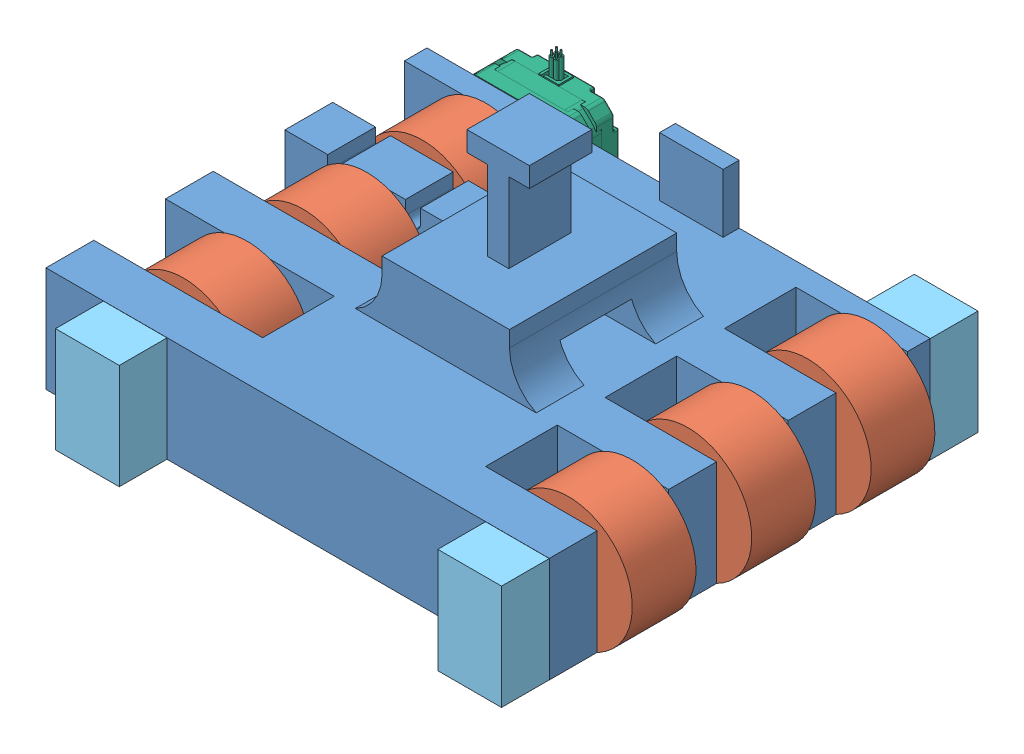
SolidWorks assembly Assembly1, configuration Default. Lengths in mm.
Overall size (224.34 121.01 190.92).
13 component instances, 6 part files, 36 mates.
Components (placement in the parent):
- Baseplate-1: Baseplate [Default] at origin size (200.66 105.14 151.88)
- Spool-1: Spool [Default] at (75.9415 19.1844 -1.5875) x (-0.044193 0.999023 0) z (-0.999023 -0.044193 0) size (50.8 25.4 50.8)
- Spool-2: Spool [Default] at (75.9415 19.1844 -49.2125) x (-0.843083 -0.537783 0) z (0.537783 -0.843083 0) size (50.8 25.4 50.8)
- Spool-4: Spool [Default] at (-77.5755 17.9234 -96.8375) x (0.161917 -0.986804 0) z (0.986804 0.161917 0) size (50.8 25.4 50.8)
- Spool-5: Spool [Default] at (-77.5755 17.9234 -49.2125) x (-0.773639 -0.633626 0) z (0.633626 -0.773639 0) size (50.8 25.4 50.8)
- Driven Axle-1: Driven Axle [Default] at (-77.5755 17.9234 -123.825) x (-0.773639 -0.633626 0) z (-0.633626 0.773639 0) size (10.56 151.89 12.19)
- Short Axle-1: Short Axle [Default] at (75.9415 19.1844 -142.35) x (-0.887276 0.46124 0) z (0.46124 0.887276 0) size (10.56 170.92 12.19)
- Axle Cap-1: Axle Cap [Default] at (76.2 19.05 -132.825) x (0 1 0) z (-1 0 0) size (41.91 28.58 25.4)
- Axle Cap-2: Axle Cap [Default] at (76.2 19.05 19.05) x (0 -1 0) z (-1 0 0) size (41.91 28.58 25.4)
- Axle Cap-3: Axle Cap [Default] at (-76.2 19.05 19.05) x (0 1 0) z (1 0 0) size (41.91 28.58 25.4)
- Spool-6: Spool [Default] at (-77.5755 17.9234 -26.9875) x (-0.773639 -0.633626 0) z (-0.633626 0.773639 0) size (50.8 25.4 50.8)
- 17HS08-1004S-1: 17HS08-1004S [По умолчанию] at (-76.2 19.05 -152.825) x (-1 0 0) z (0 1 0) size (42 40 51.2)
- Spool-7: Spool [Default] at (75.9415 19.1844 -96.8375) x (0.843083 0.537783 0) z (-0.537783 0.843083 0) size (50.8 25.4 50.8)
Mates (geometry in assembly coordinates):
- Coincident1: coincident: cylinder of Baseplate-1 through (-76.2 19.05 19.05) axis (0 0 -1) radius 6.35; line of Driven Axle-1 through (-73.7129 13.2073 28.067) axis (0 0 -1)
- Coincident2: coincident: cylinder of Baseplate-1 through (-76.2 19.05 19.05) axis (0 0 -1) radius 6.35; line of Driven Axle-1 through (-81.4381 22.6395 28.067) axis (0 0 -1)
- Coincident4: coincident: cylinder of Baseplate-1 through (76.2 19.05 19.05) axis (0 0 -1) radius 6.35; line of Short Axle-1 through (72.6632 24.3238 28.5742) axis (0 0 -1)
- Coincident5: coincident: cylinder of Baseplate-1 through (76.2 19.05 19.05) axis (0 0 -1) radius 6.35; line of Short Axle-1 through (69.8514 18.915 28.5742) axis (0 0 -1)
- Concentric1: concentric aligned: cylinder of Baseplate-1 through (76.2 34.925 9.525) axis (0 0 1) radius 3.175; cylinder of Axle Cap-2 through (76.2 34.925 9.525) axis (0 0 1) radius 3.175
- Concentric6: concentric aligned: cylinder of Baseplate-1 through (76.2 3.175 9.525) axis (0 0 1) radius 3.175; cylinder of Axle Cap-2 through (76.2 3.175 9.525) axis (0 0 1) radius 3.175
- Coincident10: coincident anti-aligned: plane of Baseplate-1 through (0 0 19.05) normal (0 0 1); plane of Axle Cap-2 through (76.2 19.05 19.05) normal (0 0 -1)
- Distance1: distance = 1.5875 mm anti-aligned: plane of Spool-1 through (75.9415 19.1844 -26.9875) normal (0 0 -1); plane of Baseplate-1 through (25.4 38.1 -28.575) normal (0 0 1)
- Distance2: distance = 1.5875 mm anti-aligned: plane of Spool-2 through (75.9415 19.1844 -49.2125) normal (0 0 1); plane of Baseplate-1 through (25.4 50.8 -47.625) normal (0 0 -1)
- Concentric7: concentric aligned: cylinder of Baseplate-1 through (76.2 34.925 -123.3) axis (0 0 -1) radius 3.175; cylinder of Axle Cap-1 through (76.2 34.925 -123.3) axis (0 0 -1) radius 3.175
- Concentric8: concentric aligned: cylinder of Baseplate-1 through (76.2 3.175 -123.3) axis (0 0 -1) radius 3.175; cylinder of Axle Cap-1 through (76.2 3.175 -123.3) axis (0 0 -1) radius 3.175
- Concentric9: concentric aligned: cylinder of Baseplate-1 through (-76.2 3.175 9.525) axis (0 0 1) radius 3.175; cylinder of Axle Cap-3 through (-76.2 3.175 9.525) axis (0 0 1) radius 3.175
- Concentric10: concentric aligned: cylinder of Baseplate-1 through (-76.2 34.925 9.525) axis (0 0 1) radius 3.175; cylinder of Axle Cap-3 through (-76.2 34.925 9.525) axis (0 0 1) radius 3.175
- Coincident27: coincident anti-aligned: plane of Baseplate-1 through (0 0 -123.825) normal (0 0 1); plane of Driven Axle-1 through (-77.5755 17.9234 -123.825) normal (0 0 -1)
- Distance3: distance = 1.5875 mm anti-aligned: plane of Spool-4 through (-77.5755 17.9234 -122.2375) normal (0 0 -1); plane of Baseplate-1 through (0 0 -123.825) normal (0 0 1)
- Distance4: distance = 1.5875 mm anti-aligned: plane of Spool-5 through (-77.5755 17.9234 -74.6125) normal (0 0 -1); plane of Baseplate-1 through (25.4 50.8 -76.2) normal (0 0 1)
- Distance5: distance = 1.5875 mm anti-aligned: plane of Spool-6 through (-77.5755 17.9234 -1.5875) normal (0 0 1); plane of Baseplate-1 through (0 0 0) normal (0 0 -1)
- Concentric11: concentric anti-aligned: cylinder of Baseplate-1 through (-91.7 34.55 -132.825) axis (0 0 1) radius 2; cylinder of 17HS08-1004S-1 through (-91.7 34.55 -132.825) axis (0 0 -1) radius 1.5
- Concentric12: concentric anti-aligned: cylinder of Baseplate-1 through (-60.7 34.55 -132.825) axis (0 0 1) radius 2; cylinder of 17HS08-1004S-1 through (-60.7 34.55 -132.825) axis (0 0 -1) radius 1.5
- Coincident35: coincident anti-aligned: plane of Baseplate-1 through (0 0 -132.825) normal (0 0 -1); plane of 17HS08-1004S-1 through (-76.2 19.05 -132.825) normal (0 0 1)
- Coincident37: coincident anti-aligned: plane of Short Axle-1 through (75.9415 19.1844 -142.35) normal (0 0 -1); plane of Axle Cap-1 through (76.2 19.05 -142.35) normal (0 0 1)
- Distance6: distance = 1.5875 mm anti-aligned: plane of Spool-7 through (75.9415 19.1844 -96.8375) normal (0 0 1); plane of Baseplate-1 through (127 38.1 -95.25) normal (0 0 -1)
- Coincident44: coincident anti-aligned: plane of Baseplate-1 through (0 0 -132.825) normal (0 0 -1); plane of Axle Cap-1 through (76.2 19.05 -132.825) normal (0 0 1)
- Coincident45: coincident anti-aligned: plane of Baseplate-1 through (0 0 19.05) normal (0 0 1); plane of Axle Cap-3 through (-76.2 19.05 19.05) normal (0 0 -1)
- Width1: width anti-aligned: plane of Spool-1 through (82.2853 19.465 -26.9875) normal (-0.887276 0.46124 0); plane of Spool-1 through (69.5977 18.9038 -26.9875) normal (0.887276 -0.46124 0); plane of Short Axle-1 through (80.6257 16.7494 28.5742) normal (0.887276 -0.46124 0); plane of Short Axle-1 through (71.2573 21.6194 28.5742) normal (-0.887276 0.46124 0)
- Width2: width anti-aligned: plane of Spool-1 through (79.3564 13.8308 -26.9875) normal (-0.044193 0.999023 0); plane of Spool-1 through (72.5266 24.538 -26.9875) normal (0.044193 -0.999023 0); plane of Short Axle-1 through (76.1748 13.9103 28.5742) normal (0.044193 -0.999023 0); plane of Short Axle-1 through (75.7082 24.4585 28.5742) normal (-0.044193 0.999023 0)
- Width3: width anti-aligned: plane of Spool-2 through (82.2853 19.465 -74.6125) normal (-0.887276 0.46124 0); plane of Spool-2 through (69.5977 18.9038 -74.6125) normal (0.887276 -0.46124 0); plane of Short Axle-1 through (80.6257 16.7494 28.5742) normal (0.887276 -0.46124 0); plane of Short Axle-1 through (71.2573 21.6194 28.5742) normal (-0.887276 0.46124 0)
- Width4: width anti-aligned: plane of Spool-2 through (79.3564 13.8308 -74.6125) normal (-0.044193 0.999023 0); plane of Spool-2 through (72.5266 24.538 -74.6125) normal (0.044193 -0.999023 0); plane of Short Axle-1 through (76.1748 13.9103 28.5742) normal (0.044193 -0.999023 0); plane of Short Axle-1 through (75.7082 24.4585 28.5742) normal (-0.044193 0.999023 0)
- Width5: width anti-aligned: plane of Spool-7 through (82.2853 19.465 -122.2375) normal (-0.887276 0.46124 0); plane of Spool-7 through (69.5977 18.9038 -122.2375) normal (0.887276 -0.46124 0); plane of Short Axle-1 through (80.6257 16.7494 28.5742) normal (0.887276 -0.46124 0); plane of Short Axle-1 through (71.2573 21.6194 28.5742) normal (-0.887276 0.46124 0)
- Width6: width anti-aligned: plane of Spool-7 through (79.3564 13.8308 -122.2375) normal (-0.044193 0.999023 0); plane of Spool-7 through (72.5266 24.538 -122.2375) normal (0.044193 -0.999023 0); plane of Short Axle-1 through (76.1748 13.9103 28.5742) normal (0.044193 -0.999023 0); plane of Short Axle-1 through (75.7082 24.4585 28.5742) normal (-0.044193 0.999023 0)
- Width7: width aligned: plane of Spool-4 through (-79.8182 11.9826 -122.2375) normal (0.773639 0.633626 0); plane of Spool-4 through (-75.3328 23.8642 -122.2375) normal (-0.773639 -0.633626 0); plane of Driven Axle-1 through (-73.4913 21.2685 28.067) normal (0.773639 0.633626 0); plane of Driven Axle-1 through (-81.6598 14.5783 28.067) normal (-0.773639 -0.633626 0)
- Width8: width anti-aligned: plane of Spool-4 through (-71.3093 18.9516 -122.2375) normal (-0.935556 0.353178 0); plane of Spool-4 through (-83.8417 16.8952 -122.2375) normal (0.935556 -0.353178 0); plane of Driven Axle-1 through (-72.6365 16.0589 28.067) normal (0.935556 -0.353178 0); plane of Driven Axle-1 through (-82.5146 19.7879 28.067) normal (-0.935556 0.353178 0)
- Width9: width aligned: plane of Spool-5 through (-79.8182 11.9826 -74.6125) normal (0.773639 0.633626 0); plane of Spool-5 through (-75.3328 23.8642 -74.6125) normal (-0.773639 -0.633626 0); plane of Driven Axle-1 through (-73.4913 21.2685 28.067) normal (0.773639 0.633626 0); plane of Driven Axle-1 through (-81.6598 14.5783 28.067) normal (-0.773639 -0.633626 0)
- Width10: width aligned: plane of Spool-5 through (-73.552 13.0108 -74.6125) normal (-0.161917 0.986804 0); plane of Spool-5 through (-81.5991 22.836 -74.6125) normal (0.161917 -0.986804 0); plane of Driven Axle-1 through (-78.4303 23.133 28.067) normal (-0.161917 0.986804 0); plane of Driven Axle-1 through (-76.7207 12.7138 28.067) normal (0.161917 -0.986804 0)
- Width11: width aligned: plane of Spool-6 through (-83.8417 16.8952 -1.5875) normal (0.773639 0.633626 0); plane of Spool-6 through (-71.3093 18.9516 -1.5875) normal (-0.773639 -0.633626 0); plane of Driven Axle-1 through (-73.4913 21.2685 28.067) normal (0.773639 0.633626 0); plane of Driven Axle-1 through (-81.6598 14.5783 28.067) normal (-0.773639 -0.633626 0)
- Width12: width aligned: plane of Spool-6 through (-81.5991 22.836 -1.5875) normal (0.935556 -0.353178 0); plane of Spool-6 through (-73.552 13.0108 -1.5875) normal (-0.935556 0.353178 0); plane of Driven Axle-1 through (-72.6365 16.0589 28.067) normal (0.935556 -0.353178 0); plane of Driven Axle-1 through (-82.5146 19.7879 28.067) normal (-0.935556 0.353178 0)
